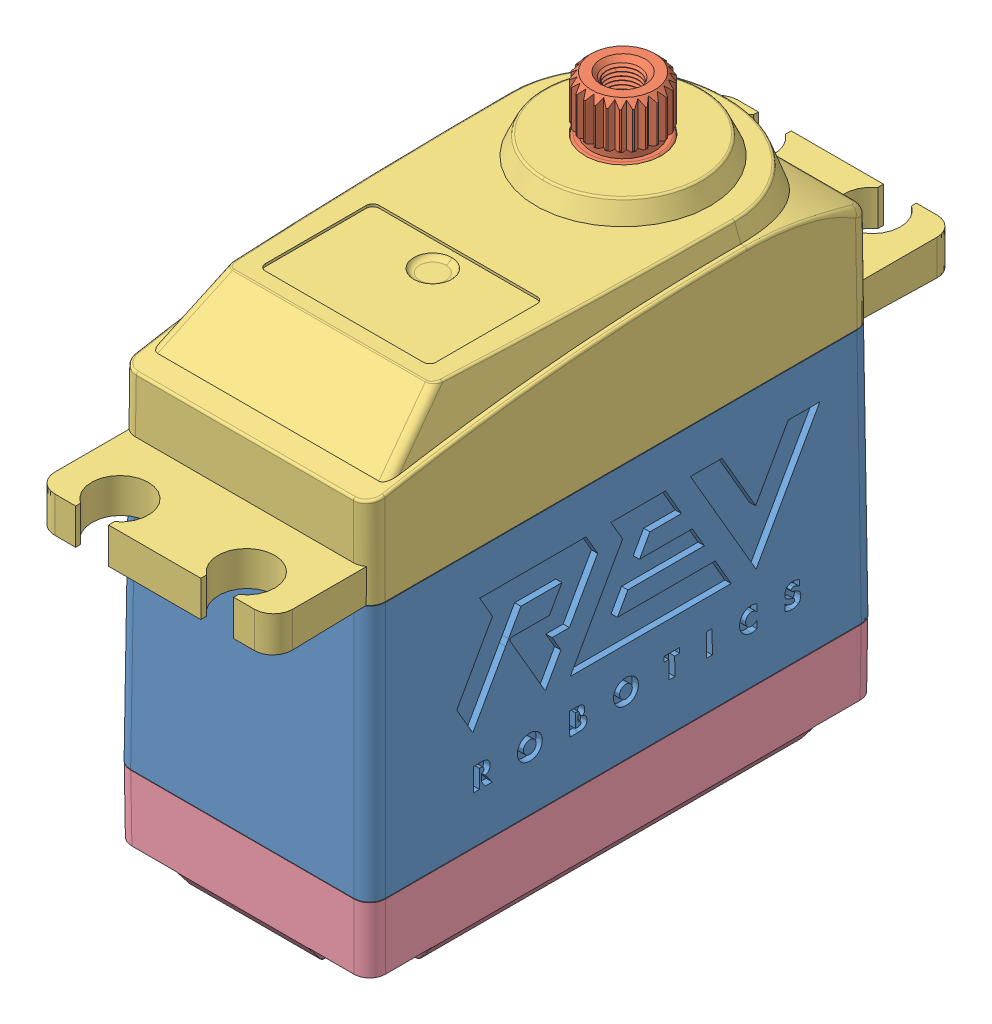
SolidWorks assembly Servo REV, configuration Valor predeterminado. Lengths in mm.
Overall size (20.15 43.7 54).
4 component instances, 4 part files, 3 mates.
Components (placement in the parent):
- E-1: E [Valor predeterminado] at (-1.9374 4.766 34.4654) size (20.15 20.1 40.15)
- D-1: D [Valor predeterminado] at (-1.9374 34.866 24.4128) x (-1 0 0) z (0 0 -1) size (17.24 14.7 17.23)
- C-1: C [Valor predeterminado] at (-1.9374 4.766 34.4654) size (19.8 13.29 54)
- A-1: A [Valor predeterminado] at (-1.9374 4.766 34.4654) size (20.15 8.55 40.13)
Mates (geometry in assembly coordinates):
- Bloquear1: lock: unknown of D-1; unknown of C-1
- Bloquear2: lock: unknown of E.step-1; unknown of C-1
- Bloquear3: lock: unknown of E.step-1; unknown of A-1
